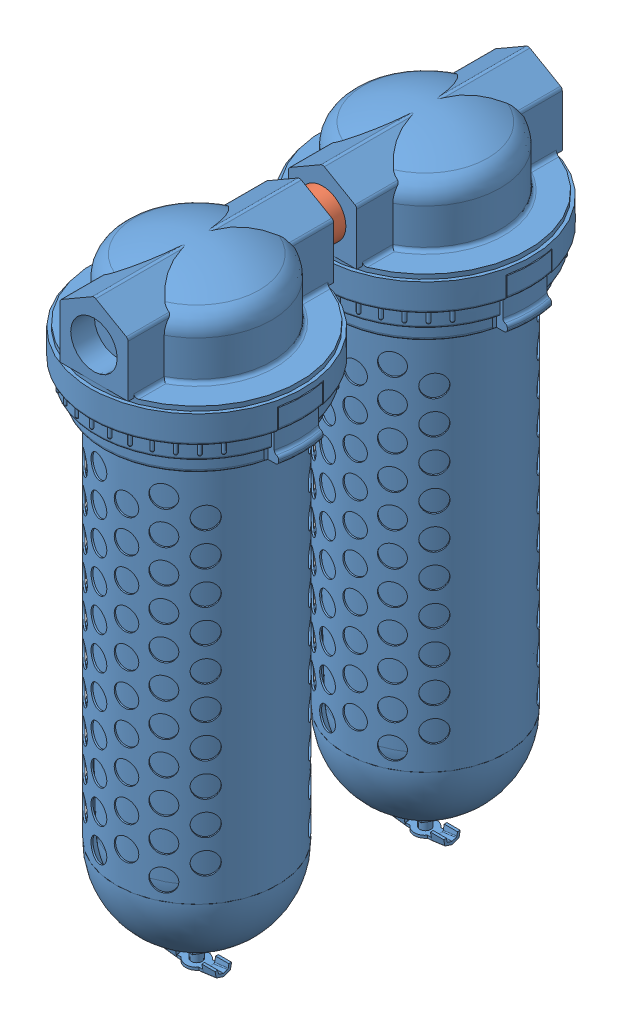
SolidWorks assembly ReadingTech_4P-090-P06-DCP, configuration Default. Lengths in mm.
Overall size (121.86 360.29 252.73).
3 component instances, 2 part files, 3 mates.
Components (placement in the parent):
- ReadingTech_3P-090-P06-P-1: ReadingTech_3P-090-P06-P [Default] at (-9.8541 -200.1722 -17.0506) size (121.86 360.29 121.67)
- ReadingTech_3P-090-P06-P-2: ReadingTech_3P-090-P06-P [Default] at (-9.8541 -200.1722 -148.1146) size (121.86 360.29 121.67)
- ReadingTech- 90,150cfm_connector_.75in-1: ReadingTech- 90,150cfm_connector_.75in [Default] at (-9.8541 188.8288 -75.9786) x (1 0 0) z (0 1 0) size (26.67 13.21 26.67)
Mates (geometry in assembly coordinates):
- Coincident2: coincident anti-aligned: circle of ReadingTech_3P-090-P06-P-2; circle of ReadingTech- 90,150cfm_connector_.75in-1
- Coincident3: coincident aligned: circle of ReadingTech_3P-090-P06-P-1; circle of ReadingTech- 90,150cfm_connector_.75in-1
- Coincident4: coincident aligned: plane of ReadingTech_3P-090-P06-P-1 through (9.7039 201.5288 41.8774) normal (1 0 0); plane of ReadingTech_3P-090-P06-P-2 through (9.7039 201.5288 -89.1866) normal (1 0 0)
